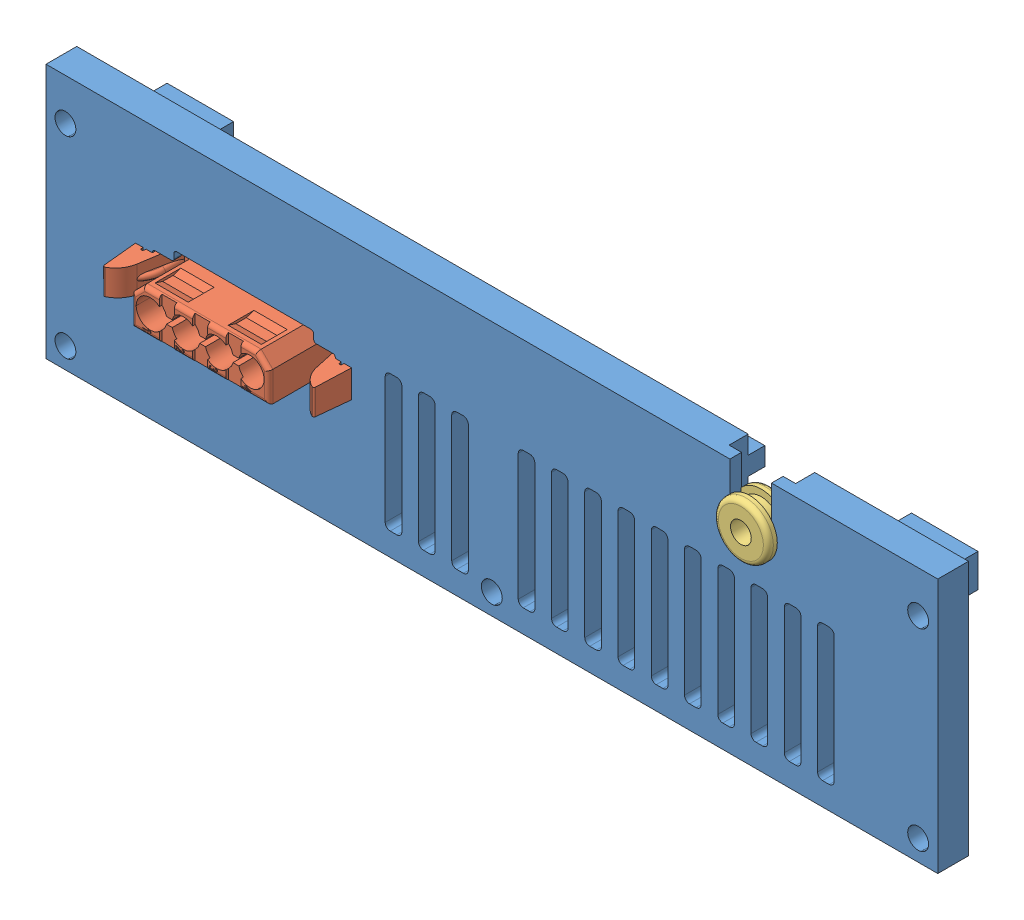
SolidWorks assembly Complete_Back_panel, configuration Default. Lengths in mm.
Overall size (136.22 38.96 21.68).
3 component instances, 3 part files, 6 mates.
Components (placement in the parent):
- Back_plate-1: Back_plate [Default] at (-9.9495 80.3418 130.3548) size (136.22 38.96 12.32)
- AMP-1-480425-0-1: AMP-1-480425-0 [Default] at (20.2303 100.8744 141.6899) x (0 -1 0) z (0 0 1) size (16.26 33.21 21.68)
- Grommet_330-1: Grommet_330 [Default] at (97.5687 111.8124 131.955) x (0.966477 0.256755 0) z (0.256755 -0.966477 0) size (8.38 4.47 8.38)
Mates (geometry in assembly coordinates):
- Parallel3: parallel anti-aligned: line of Back_plate-1 through (-9.9495 80.3418 130.3548) axis (1 0 0); line of AMP-1-480425-0-1 through (26.1358 108.7484 133.8159) axis (-1 0 0)
- Distance1: distance = 19.7023 mm aligned: plane of AMP-1-480425-0-1 through (9.7528 100.8744 141.6899) normal (-1 0 0); plane of Back_plate-1 through (-9.9495 80.3418 135.0538) normal (-1 0 0)
- Distance2: distance = 15.256 mm aligned: plane of AMP-1-480425-0-1 through (30.7078 104.0494 141.6899) normal (0 1 0); plane of Back_plate-1 through (-9.9495 119.3054 135.0538) normal (0 1 0)
- Distance3: distance = 13.8109 mm aligned: plane of AMP-1-480425-0-1 through (30.7078 104.0494 120.0999) normal (0 0 -1); plane of Back_plate-1 through (-9.9495 80.3418 133.9108) normal (0 0 -1)
- Coincident1: coincident anti-aligned: plane of Back_plate-1 through (-9.9495 80.3418 135.0538) normal (0 0 1); plane of Grommet_330-1 through (97.5687 111.8124 135.0538) normal (0 0 -1)
- Concentric1: concentric aligned: circle of Back_plate-1; circle of Grommet_330-1
